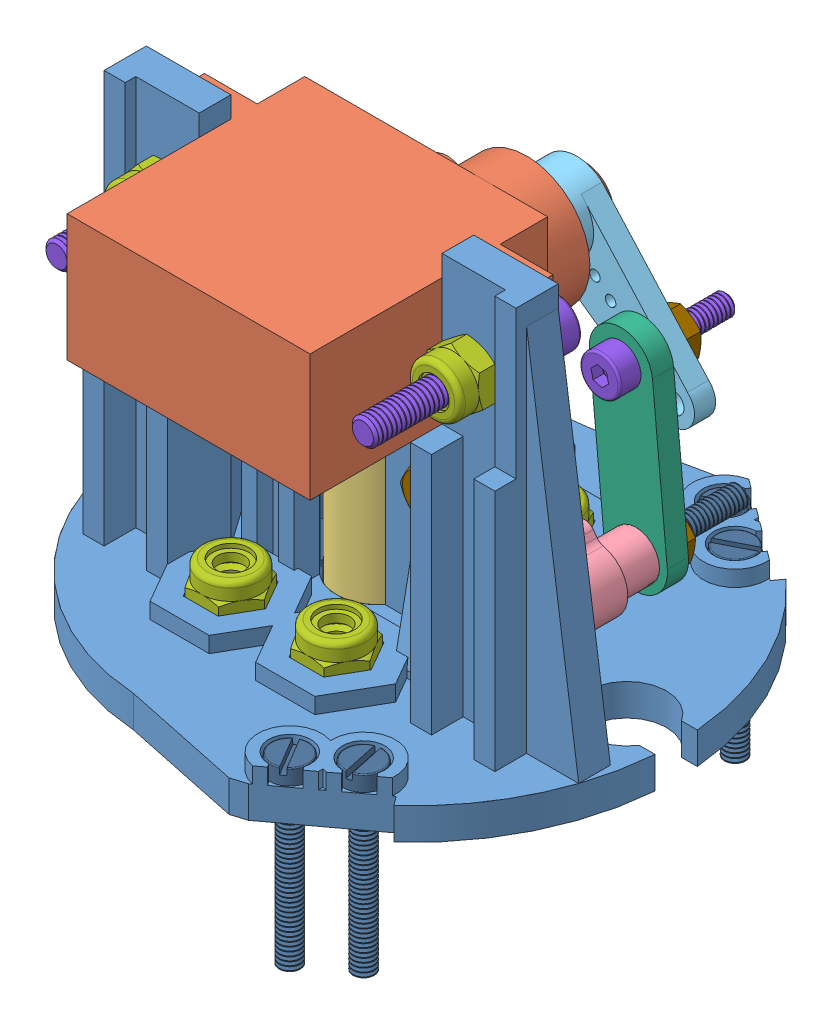
SolidWorks assembly Rückseite, configuration Standard. Lengths in mm.
Overall size (49.92 53 48.18).
27 component instances, 11 part files, 59 mates.
Components (placement in the parent):
- Backside-1: Backside [Standard] at (-0.7502 -6.4244 50) size (49.92 40 48.18)
- servo-1: servo [Standard] at (-9.7502 31.5756 70.5) x (1 0 0) z (0 1 0) size (33 29.25 12)
- Druecker-1: Druecker [Standard] at (-0.7502 19.5776 50) x (1 0 0) z (0 0 -1) size (7.5 31.5 7.5)
- Hebel-1: Hebel [Standard] at (9.2498 10.5756 51) x (0.969542 -0.244925 0) z (0 0 -1) size (27.06 14 7.75)
- Servo-Arm-1: Servo-Arm [Standard] at (7.2498 25.5756 39.25) x (0.743788 -0.668416 0) z (-0.668416 -0.743788 0) size (20.6 4.3 7.2)
- Hebel2-1: Hebel2 [Standard] at (16.8394 3.2893 41.25) x (-0.093858 0.995586 0) z (0.995586 0.093858 0) size (21 2 6)
- User Library-Mutter DIN-985_-1: User Library-Mutter DIN-985_ [Mutter DIN-985 M3-A2] at (-4.7502 -3.4244 60) x (0 1 0) z (0 0 1) size (4 6.35 5.5)
- User Library-Mutter DIN-985_-2: User Library-Mutter DIN-985_ [Mutter DIN-985 M3-A2] at (5.2498 -3.4244 60) x (0 1 0) z (-0.866025 0 0.5) size (4 6.35 5.5)
- User Library-Mutter DIN-985_-3: User Library-Mutter DIN-985_ [Mutter DIN-985 M3-A2] at (5.2498 -3.4244 40) x (0 1 0) z (-0.866025 0 -0.5) size (4 6.35 5.5)
- User Library-Mutter DIN-985_-4: User Library-Mutter DIN-985_ [Mutter DIN-985 M3-A2] at (-4.7502 -3.4244 40) x (0 1 0) z (-0.866025 0 0.5) size (4 6.35 5.5)
- socket head cap screw 4762_din-1: socket head cap screw 4762_din [ISO 4762 M2 x 10 --- 10S] at (9.2498 10.5756 43.8) x (0 0 1) z (0.327477 -0.944859 0) size (12 3.8 3.8)
- socket head cap screw 4762_din-2: socket head cap screw 4762_din [ISO 4762 M2 x 10 --- 10S] at (-0.7502 15.5776 55.25) x (0 0 -1) z (0.060223 0.998185 0) size (12 3.8 3.8)
- socket head cap screw 4762_din-3: socket head cap screw 4762_din [ISO 4762 M2 x 10 --- 10S] at (15.4315 18.2231 45.25) x (0 0 -1) z (-0.697004 0.717067 0) size (12 3.8 3.8)
- nut__style_1__m2x0_4__ansi_b18_2_4_1m-1: nut__style_1__m2x0_4__ansi_b18_2_4_1m [Default] at (-0.7502 15.5776 46.75) x (0.866025 -0.5 0) z (0 0 -1) size (4.62 4 1.6)
- nut__style_1__m2x0_4__ansi_b18_2_4_1m-2: nut__style_1__m2x0_4__ansi_b18_2_4_1m [Default] at (15.4315 18.2231 37.65) x (-0.820318 0.571907 0) z (0 0 1) size (4.62 4 1.6)
- nut__style_1__m2x0_4__ansi_b18_2_4_1m-3: nut__style_1__m2x0_4__ansi_b18_2_4_1m [Default] at (9.2498 10.5756 54.2) x (0.532315 -0.846547 0) z (0 0 1) size (4.62 4 1.6)
- User Library-Mutter DIN-985_-5: User Library-Mutter DIN-985_ [Mutter DIN-985 M2,5-A2] at (-12.7502 25.5756 58) x (0 0 1) z (-0.937505 -0.347973 0) size (3.8 5.77 5)
- User Library-Mutter DIN-985_-6: User Library-Mutter DIN-985_ [Mutter DIN-985 M2,5-A2] at (16.2498 25.5756 58) x (0 0 1) z (-0.395566 -0.918438 0) size (3.8 5.77 5)
- slotted cheese head screw_din-1: slotted cheese head screw_din [ISO 1207 - M2 x 16 --- 16S] at (11.3929 -2.0244 70.5635) x (0 -1 0) z (0.511563 0 0.859246) size (17.41 3.8 3.8)
- slotted cheese head screw_din-2: slotted cheese head screw_din [ISO 1207 - M2 x 16 --- 16S] at (11.3929 -2.0244 29.4365) x (0 -1 0) z (-0.876101 0 0.482128) size (17.41 3.8 3.8)
- slotted cheese head screw_din-3: slotted cheese head screw_din [ISO 1207 - M2 x 16 --- 16S] at (15.4084 -2.0244 32.4156) x (0 -1 0) z (-0.890448 0 0.455085) size (17.41 3.8 3.8)
- slotted cheese head screw_din-4: slotted cheese head screw_din [ISO 1207 - M2 x 16 --- 16S] at (15.4084 -2.0244 67.5844) x (0 -1 0) z (0.212665 0 0.977125) size (17.41 3.8 3.8)
- slotted cheese head screw_din-5: slotted cheese head screw_din [ISO 1207 - M2 x 16 --- 16S] at (16.8394 3.2893 50.85) x (0 0 -1) z (0.575115 0.818073 0) size (17.41 3.8 3.8)
- nut__style_1__m2x0_4__ansi_b18_2_4_1m-4: nut__style_1__m2x0_4__ansi_b18_2_4_1m [Default] at (16.8394 3.2893 41.25) x (-0.746648 0.66522 0) z (0 0 -1) size (4.62 4 1.6)
- cross fh tapping 7976_din-2: cross fh tapping 7976_din [Tapping screw DIN 7982-ST2.9x6.5-C-Z-S] at (7.2498 25.5756 38.5) x (0 0 1) z (-0.95506 0.296413 0) size (6.51 5.5 5.5)
- socket head cap screw 4762_din-4: socket head cap screw 4762_din [ISO 4762 M2.5 x 16 --- 16S] at (-12.7502 25.5756 50) x (0 0 1) z (0.225641 0.974211 0) size (18.5 4.5 4.5)
- socket head cap screw 4762_din-5: socket head cap screw 4762_din [ISO 4762 M2.5 x 16 --- 16S] at (16.2498 25.5756 50) x (0 0 1) z (-0.799016 -0.60131 0) size (18.5 4.5 4.5)
Mates (geometry in assembly coordinates):
- Konzentrisch1: concentric anti-aligned: cylinder of Druecker-1 through (-0.7502 -11.9224 50) axis (0 1 0) radius 3.75; cylinder of Backside-1 through (-0.7502 -3.4244 50) axis (0 -1 0) radius 4
- Konzentrisch2: concentric aligned: cylinder of Backside-1 through (9.2498 10.5756 57.5) axis (0 0 1) radius 1.15; cylinder of Hebel-1 through (9.2498 10.5756 49) axis (0 0 1) radius 1.15
- Deckungsgleich1: coincident anti-aligned: plane of Hebel-1 through (9.2498 10.5756 49) normal (0 0 -1); plane of Backside-1 through (6.7498 13.5756 49) normal (0 0 1)
- Parallel1: parallel anti-aligned: plane of Druecker-1 through (-5.7502 11.5776 51) normal (0 0 -1); plane of Hebel-1 through (9.2498 10.5756 51) normal (0 0 1)
- Langloch1: slot anti-aligned: cylinder of Druecker-1 through (-0.7512 15.5756 54) axis (0 0 -1) radius 1.1; cylinder of Hebel-1 through (0.9786 14.066 49) axis (0 0 1) radius 1.15; cylinder of Hebel-1 through (-1.8989 16.8445 49) axis (0 0 1) radius 1.15
- Konzentrisch3: concentric anti-aligned: cylinder of servo-1 through (7.2498 25.5756 44) axis (0 0 1) radius 6; cylinder of Servo-Arm-1 through (7.2498 25.5756 43.55) axis (0 0 -1) radius 2.25
- Deckungsgleich6: coincident anti-aligned: plane of Backside-1 through (-9.7502 31.5756 58) normal (1 0 0); plane of servo-1 through (-9.7502 31.5756 48) normal (-1 0 0)
- Deckungsgleich7: coincident anti-aligned: plane of servo-1 through (18.2498 31.5756 55) normal (0 0 1); plane of Backside-1 through (-17.7502 19.5756 55) normal (0 0 -1)
- Deckungsgleich9: coincident anti-aligned: plane of Hebel2-1 through (16.8394 3.2893 41.25) normal (0 0 -1); plane of Servo-Arm-1 through (7.2498 25.5756 41.25) normal (0 0 1)
- Konzentrisch4: concentric anti-aligned: cylinder of Hebel-1 through (16.8394 3.2893 47) axis (0 0 1) radius 1.15; cylinder of Hebel2-1 through (16.8394 3.2893 43.25) axis (0 0 -1) radius 1.15
- Deckungsgleich12: coincident anti-aligned: plane of servo-1 through (7.2498 25.5756 41.25) normal (0 0 -1); plane of Servo-Arm-1 through (7.2498 25.5756 41.25) normal (0 0 1)
- Konzentrisch5: concentric aligned: cylinder of Servo-Arm-1 through (15.4315 18.2231 41.25) axis (0 0 -1) radius 0.5; cylinder of Hebel2-1 through (15.4315 18.2231 43.25) axis (0 0 -1) radius 1.15
- Deckungsgleich28: coincident anti-aligned: plane of Backside-1 through (-0.7502 -3.4244 50) normal (0 1 0); plane of User Library-Mutter DIN-985_-1 through (-7.4789 -3.4244 60) normal (0 -1 0)
- Deckungsgleich29: coincident anti-aligned: plane of Backside-1 through (-0.7502 -3.4244 50) normal (0 1 0); plane of User Library-Mutter DIN-985_-2 through (3.8855 -3.4244 57.6369) normal (0 -1 0)
- Deckungsgleich31: coincident anti-aligned: plane of Backside-1 through (-0.7502 -3.4244 50) normal (0 1 0); plane of User Library-Mutter DIN-985_-3 through (6.6142 -3.4244 37.6369) normal (0 -1 0)
- Deckungsgleich30: coincident anti-aligned: plane of Backside-1 through (-0.7502 -3.4244 50) normal (0 1 0); plane of User Library-Mutter DIN-985_-4 through (-6.1145 -3.4244 37.6369) normal (0 -1 0)
- Deckungsgleich21: coincident anti-aligned: plane of Backside-1 through (9.2498 10.5756 45.8) normal (0 0 -1); plane of socket head cap screw 4762_din-1 through (7.4546 9.9534 45.8) normal (0 0 1)
- Konzentrisch20: concentric anti-aligned: cylinder of Backside-1 through (9.2498 10.5756 57.5) axis (0 0 1) radius 1.15; cylinder of socket head cap screw 4762_din-1 through (9.2498 10.5756 12.05) axis (0 0 -1) radius 1
- Konzentrisch19: concentric anti-aligned: cylinder of Druecker-1 through (-0.7502 15.5776 54) axis (0 0 -1) radius 1.1; cylinder of socket head cap screw 4762_din-2 through (-0.7502 15.5776 87) axis (0 0 1) radius 1
- Deckungsgleich38: coincident anti-aligned: plane of Hebel2-1 through (16.8394 3.2893 43.25) normal (0 0 1); plane of socket head cap screw 4762_din-3 through (14.0691 16.8987 43.25) normal (0 0 -1)
- Konzentrisch38: concentric anti-aligned: cylinder of Hebel2-1 through (15.4315 18.2231 43.25) axis (0 0 -1) radius 1.15; cylinder of socket head cap screw 4762_din-3 through (15.4315 18.2231 77) axis (0 0 1) radius 1
- Deckungsgleich41: coincident anti-aligned: plane of Druecker-1 through (-0.7502 19.5776 46.75) normal (0 0 -1); plane of nut__style_1__m2x0_4__ansi_b18_2_4_1m-1 through (1.2503 14.4226 46.75) normal (0 0 1)
- Konzentrisch49: concentric aligned: circle of socket head cap screw 4762_din-2; circle of nut__style_1__m2x0_4__ansi_b18_2_4_1m-1
- Deckungsgleich39: coincident anti-aligned: plane of Servo-Arm-1 through (7.2498 25.5756 39.25) normal (0 0 -1); plane of nut__style_1__m2x0_4__ansi_b18_2_4_1m-2 through (13.5366 19.5442 39.25) normal (0 0 1)
- Konzentrisch50: concentric anti-aligned: circle of socket head cap screw 4762_din-3; circle of nut__style_1__m2x0_4__ansi_b18_2_4_1m-2
- Deckungsgleich33: coincident anti-aligned: plane of Backside-1 through (9.2498 10.5756 54.2) normal (0 0 1); plane of nut__style_1__m2x0_4__ansi_b18_2_4_1m-3 through (10.4795 8.6201 54.2) normal (0 0 -1)
- Konzentrisch48: concentric aligned: circle of socket head cap screw 4762_din-1; circle of nut__style_1__m2x0_4__ansi_b18_2_4_1m-3
- Deckungsgleich36: coincident anti-aligned: plane of Backside-1 through (-11.7502 31.5756 58) normal (0 0 1); plane of User Library-Mutter DIN-985_-5 through (-13.5593 27.7554 58) normal (0 0 -1)
- Deckungsgleich37: coincident anti-aligned: plane of Backside-1 through (15.2498 31.5756 58) normal (0 0 1); plane of User Library-Mutter DIN-985_-6 through (14.1143 26.4954 58) normal (0 0 -1)
- Konzentrisch51: concentric aligned: circle of Backside-1; circle of User Library-Mutter DIN-985_-1
- Konzentrisch52: concentric aligned: circle of Backside-1; circle of User Library-Mutter DIN-985_-2
- Konzentrisch53: concentric aligned: circle of Backside-1; circle of User Library-Mutter DIN-985_-4
- Konzentrisch54: concentric aligned: circle of Backside-1; circle of User Library-Mutter DIN-985_-3
- Konzentrisch55: concentric aligned: circle of User Library-Mutter DIN-985_-5; cylinder of Backside-1 through (-12.7502 25.5756 41) axis (0 0 1) radius 1.25
- Konzentrisch56: concentric aligned: circle of User Library-Mutter DIN-985_-6; cylinder of Backside-1 through (16.2498 25.5756 41) axis (0 0 1) radius 1.25
- Deckungsgleich40: coincident anti-aligned: plane of Druecker-1 through (-0.7502 15.5776 53.25) normal (0 0 1); plane of socket head cap screw 4762_din-2 through (-2.6467 15.692 53.25) normal (0 0 -1)
- Konzentrisch59: concentric aligned: cylinder of Backside-1 through (15.4084 -13.4244 32.4156) axis (0 1 0) radius 1.1; cylinder of slotted cheese head screw_din-3 through (15.4084 23.3756 32.4156) axis (0 1 0) radius 1
- Konzentrisch60: concentric aligned: cylinder of Backside-1 through (11.3929 -13.4244 29.4365) axis (0 1 0) radius 1.1; cylinder of slotted cheese head screw_din-2 through (11.3929 23.3756 29.4365) axis (0 1 0) radius 1
- Konzentrisch61: concentric aligned: cylinder of Backside-1 through (15.4084 -13.4244 67.5844) axis (0 1 0) radius 1.1; cylinder of slotted cheese head screw_din-4 through (15.4084 23.3756 67.5844) axis (0 1 0) radius 1
- Konzentrisch62: concentric aligned: cylinder of Backside-1 through (11.3929 -13.4244 70.5635) axis (0 1 0) radius 1.1; cylinder of slotted cheese head screw_din-1 through (11.3929 23.3756 70.5635) axis (0 1 0) radius 1
- Deckungsgleich42: coincident anti-aligned: plane of Backside-1 through (-0.7502 -3.4244 50) normal (0 1 0); plane of slotted cheese head screw_din-3 through (15.8635 -3.4244 33.306) normal (0 -1 0)
- Deckungsgleich43: coincident anti-aligned: plane of Backside-1 through (-0.7502 -3.4244 50) normal (0 1 0); plane of slotted cheese head screw_din-2 through (11.875 -3.4244 30.3126) normal (0 -1 0)
- Deckungsgleich44: coincident anti-aligned: plane of Backside-1 through (-0.7502 -3.4244 50) normal (0 1 0); plane of slotted cheese head screw_din-1 through (12.2521 -3.4244 70.052) normal (0 -1 0)
- Deckungsgleich45: coincident anti-aligned: plane of Backside-1 through (-0.7502 -3.4244 50) normal (0 1 0); plane of slotted cheese head screw_din-4 through (16.3856 -3.4244 67.3717) normal (0 -1 0)
- Konzentrisch64: concentric aligned: cylinder of Hebel-1 through (16.8394 3.2893 47) axis (0 0 1) radius 1.15; cylinder of slotted cheese head screw_din-5 through (16.8394 3.2893 76.25) axis (0 0 1) radius 1
- Deckungsgleich47: coincident aligned: circle of Hebel-1; plane of slotted cheese head screw_din-5 through (16.0213 3.8644 49.45) normal (0 0 -1)
- Deckungsgleich48: coincident anti-aligned: plane of Hebel2-1 through (16.8394 3.2893 41.25) normal (0 0 -1); plane of nut__style_1__m2x0_4__ansi_b18_2_4_1m-4 through (15.1146 4.8259 41.25) normal (0 0 1)
- Konzentrisch65: concentric anti-aligned: cylinder of Hebel2-1 through (16.8394 3.2893 43.25) axis (0 0 -1) radius 1.15; cylinder of nut__style_1__m2x0_4__ansi_b18_2_4_1m-4 through (16.8394 3.2893 41.25) axis (0 0 1) radius 0.7835
- Deckungsgleich50: coincident: circle of Servo-Arm-1; cone of cross fh tapping 7976_din-2 through (7.2498 25.5756 40.2) axis (0 0 1)
- Parallel2: parallel anti-aligned: plane of Backside-1 through (10.5481 -1.9244 43.4769) normal (-0.866025 0 0.5); plane of User Library-Mutter DIN-985_-3 through (8.4252 0.5766 40) normal (0.866025 0 -0.5)
- Parallel3: parallel anti-aligned: plane of Backside-1 through (3.0481 -1.9244 47.8071) normal (-0.866025 0 0.5); plane of User Library-Mutter DIN-985_-4 through (-1.5748 0.5766 40) normal (0.866025 0 -0.5)
- Parallel4: parallel anti-aligned: plane of Backside-1 through (3.0481 -1.9244 52.1929) normal (-0.866025 0 -0.5); plane of User Library-Mutter DIN-985_-1 through (-3.1625 0.5766 62.75) normal (0.866025 0 0.5)
- Parallel5: parallel anti-aligned: plane of Backside-1 through (10.5481 -1.9244 56.5231) normal (-0.866025 0 -0.5); plane of User Library-Mutter DIN-985_-2 through (6.8375 0.5766 62.75) normal (0.866025 0 0.5)
- Parallel6: parallel anti-aligned: plane of Druecker-1 through (-2.8002 16.7612 46.75) normal (0.5 -0.866025 0); plane of nut__style_1__m2x0_4__ansi_b18_2_4_1m-1 through (-2.7507 16.7326 45.15) normal (-0.5 0.866025 0)
- Deckungsgleich51: coincident anti-aligned: plane of Backside-1 through (-0.7502 19.5756 50) normal (0 1 0); plane of servo-1 through (-9.7502 19.5756 48) normal (0 -1 0)
- Konzentrisch66: concentric anti-aligned: circle of socket head cap screw 4762_din-4; circle of User Library-Mutter DIN-985_-5
- Konzentrisch67: concentric anti-aligned: circle of socket head cap screw 4762_din-5; circle of User Library-Mutter DIN-985_-6
- Deckungsgleich52: coincident anti-aligned: plane of servo-1 through (18.2498 31.5756 52.5) normal (0 0 -1); plane of socket head cap screw 4762_din-5 through (14.8969 27.3734 52.5) normal (0 0 1)
- Deckungsgleich53: coincident anti-aligned: plane of servo-1 through (18.2498 31.5756 52.5) normal (0 0 -1); plane of socket head cap screw 4762_din-4 through (-10.5582 25.0679 52.5) normal (0 0 1)
